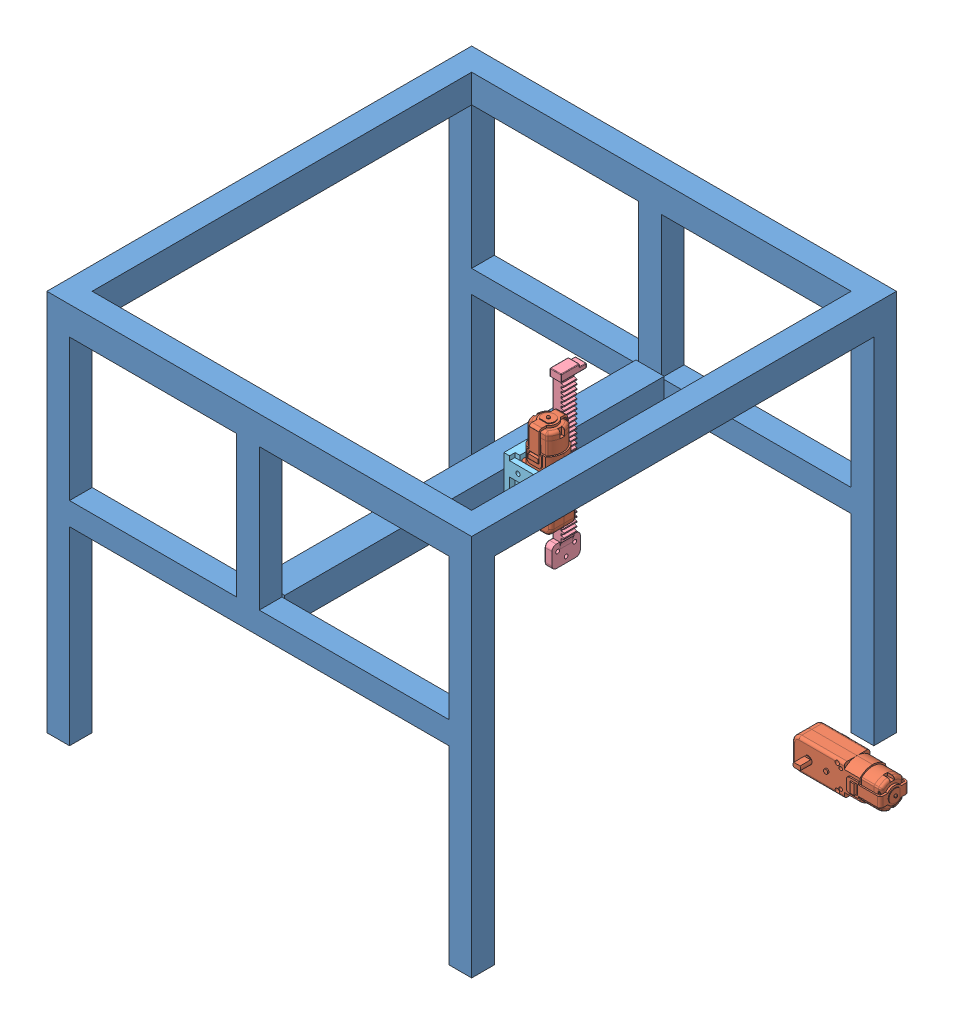
SolidWorks assembly full, configuration Default. Lengths in mm.
Overall size (325.17 294.87 300).
7 component instances, 5 part files, 3 mates.
Components (placement in the parent):
- base-1: base [Default] at (-44.6114 125.6891 16.2788) size (300 270 300)
- Motor DC-1: Motor DC [Default] at (101.2467 -110.3564 -141.3772) size (70 22 34.5)
- RackNpinion-1: RackNpinion [Default] at (-41.7211 85.9924 1.6101) x (0 1 0) z (0 0 -1) size (120 32 50.5)
  - Motor DC-1: Motor DC [Default] at (-52.6107 45.4391 -13.6039) size (70 22 34.5)
  - Gear RnP-1: Gear RnP [Default] at (-52.6107 45.4391 28.5521) size (15.96 15.88 16.5)
  - Rack RnP-1: Rack RnP [Default] at (-52.6107 45.4391 45.0521) size (120 8.01 21.5)
  - BaseRnP-1: BaseRnP [Default] at (-52.6107 3.6097 45.0521) x (-1 0 0) z (0 -1 0) size (40 42 32)
Mates (geometry in assembly coordinates):
- Coincident1: coincident anti-aligned: plane of base-1 through (-178.6114 145.6891 -117.7212) normal (0 0 1); plane of Motor DC-1 through (84.0541 -138.1857 -117.7212) normal (0 0 -1)
- Coincident2: coincident anti-aligned: plane of base-1 through (-42.6114 27.6891 -146.0055) normal (1 0 0); plane of RackNpinion-1/BaseRnP-1 through (-42.6114 33.3818 -43.442) normal (-1 0 0)
- Width1: width anti-aligned: plane of RackNpinion-1/BaseRnP-1 through (-42.6114 37.6891 -46.442) normal (0 1 0); plane of base-1 through (-40.6114 -2.3109 -32.442) normal (0 -1 0); plane of RackNpinion-1/BaseRnP-1 through (-42.6114 7.6891 -146.0055) normal (0 -1 0); plane of base-1 through (-42.6114 27.6891 -146.0055) normal (0 1 0)
